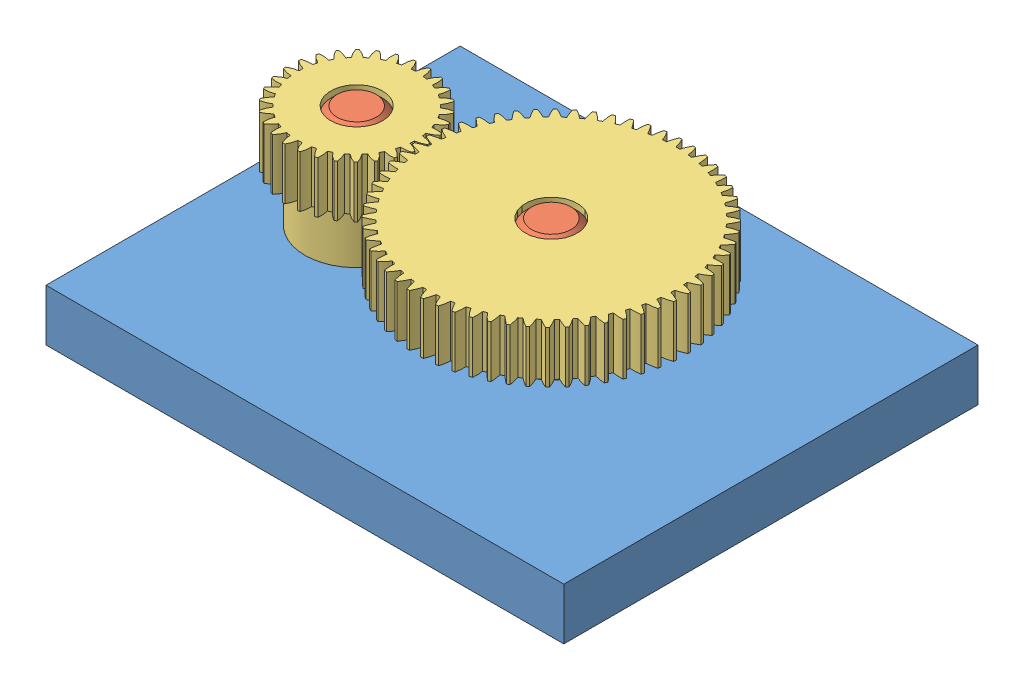
SolidWorks assembly Wang_GearAssembly, configuration Default. Lengths in mm.
Overall size (127 38.1 101.6).
5 component instances, 3 part files, 9 mates.
Components (placement in the parent):
- Wang_BasePlate-1: Wang_BasePlate [Default] at origin size (127 12.7 101.6)
- Wang_Shaft-1: Wang_Shaft [Default] at (-38.1 0 0) x (0 1 0) z (0.990913 0 0.134506) size (38.1 12.7 12.7)
- Wang_Shaft-2: Wang_Shaft [Default] at (9.652 0 0) x (0 1 0) z (0.502336 0 0.864673) size (38.1 12.7 12.7)
- spur gear_ai-1: spur gear_ai [Inch - Spur gear 24DP 30T 20PA 0.5FW ---S30O1H1L0.5N] at (-38.1 25.4 0) x (0 1 0) z (0.148631 0 0.988893) size (25.4 33.74 33.87)
- spur gear_ai-2: spur gear_ai [Inch - Spur gear 24DP 60T 20PA 0.5FW ---S60O1H1L0.5N] at (9.652 25.4 0) x (0 1 0) z (-0.124682 0 0.992197) size (25.4 65.56 65.56)
Mates (geometry in assembly coordinates):
- Concentric1: concentric anti-aligned: circle of Wang_BasePlate-1; circle of Wang_Shaft-1
- Distance1: distance = 25.4 mm aligned: plane of Wang_Shaft-1 through (-38.1 38.1 0) normal (0 1 0); plane of Wang_BasePlate-1 through (0 12.7 0) normal (0 1 0)
- Concentric2: concentric anti-aligned: circle of Wang_BasePlate-1; circle of Wang_Shaft-2
- Distance2: distance = 25.4 mm aligned: plane of Wang_Shaft-2 through (9.652 38.1 0) normal (0 1 0); plane of Wang_BasePlate-1 through (0 12.7 0) normal (0 1 0)
- Concentric3: concentric anti-aligned: circle of Wang_Shaft-1; circle of spur gear_ai-1
- Coincident1: coincident aligned: plane of Wang_Shaft-1 through (-38.1 38.1 0) normal (0 1 0); plane of spur gear_ai-1 through (-38.1 38.1 0) normal (0 1 0)
- Concentric4: concentric anti-aligned: circle of Wang_Shaft-2; circle of spur gear_ai-2
- Coincident2: coincident aligned: plane of Wang_Shaft-2 through (9.652 38.1 0) normal (0 1 0); plane of spur gear_ai-2 through (9.652 38.1 0) normal (0 1 0)
- GearMate1: gear = 63.5 : 31.75 mm: circle of spur gear_ai-1; circle of spur gear_ai-2
